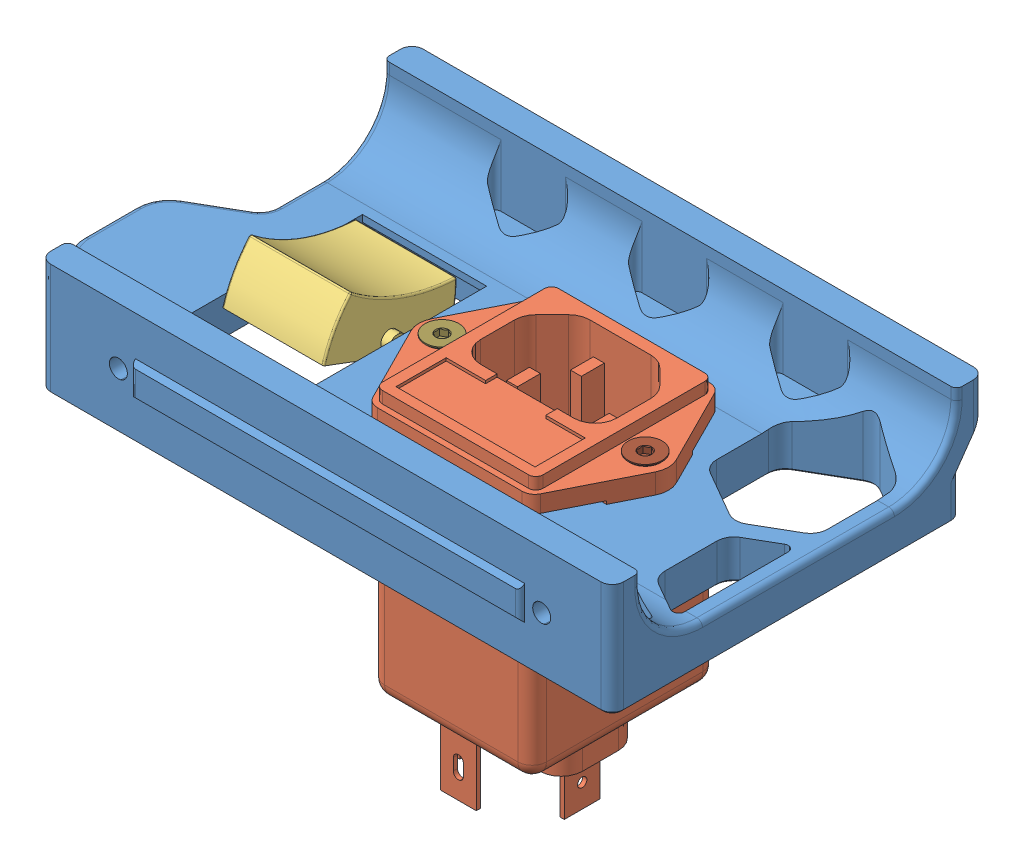
SolidWorks assembly power_inlet, configuration Default. Lengths in mm.
Overall size (114 66.75 66.8).
15 component instances, 13 part files, 0 mates.
Components (placement in the parent):
- Filtered-1: Filtered [Default] at origin size (114 20 66.8)
- c-3-1609115-3-a-1: c-3-1609115-3-a [Default] at (-90.9243 562.2112 85.6842) x (1 0 0) z (0 1 0) size (44.2 33.56 59.39)
- Switch DPST-1: Switch DPST [Default] at (-234.7743 556.5724 177.1842) x (0 -1 0) z (1 0 0) size (34.47 23.68 21)
  - Switch DPST (1)-1: Switch DPST (1) [Default] at origin size (34.47 23.68 21)
    - 8008_5430-1: 8008_5430 [Default] at origin
    - 8008_5938-1: 8008_5938 [Default] at origin size (16.91 23.68 21)
    - 8008_6210-1: 8008_6210 [Default] at origin size (15.18 21.7 16)
    - 8009_461-1: 8009_461 [Default] at origin size (9.5 0.7 9)
    - 8009_2302-1: 8009_2302 [Default] at origin size (9.5 0.7 9)
    - 8009_2553-1: 8009_2553 [Default] at origin size (9.5 0.7 9)
    - 8009_2706-1: 8009_2706 [Default] at origin size (9.5 0.7 9)
- M3 Threaded Insert (51)-1: M3 Threaded Insert (51) [Default] at (-72.9243 552.7224 85.6842) x (1 0 0) z (0 1 0) size (5 5 3.85)
- M3 Threaded Insert (50)-1: M3 Threaded Insert (50) [Default] at (-108.9243 552.7224 85.6842) x (1 0 0) z (0 1 0) size (5 5 3.85)
- M3x10 FHCS-1: M3x10 FHCS [Default] at (-72.9284 560.6284 85.6842) x (1 0 0) z (0 1 0) size (6 6 10.12)
- M3x10 FHCS (1)-1: M3x10 FHCS (1) [Default] at (-108.9284 560.6284 85.6842) x (1 0 0) z (0 1 0) size (6 6 10.12)
